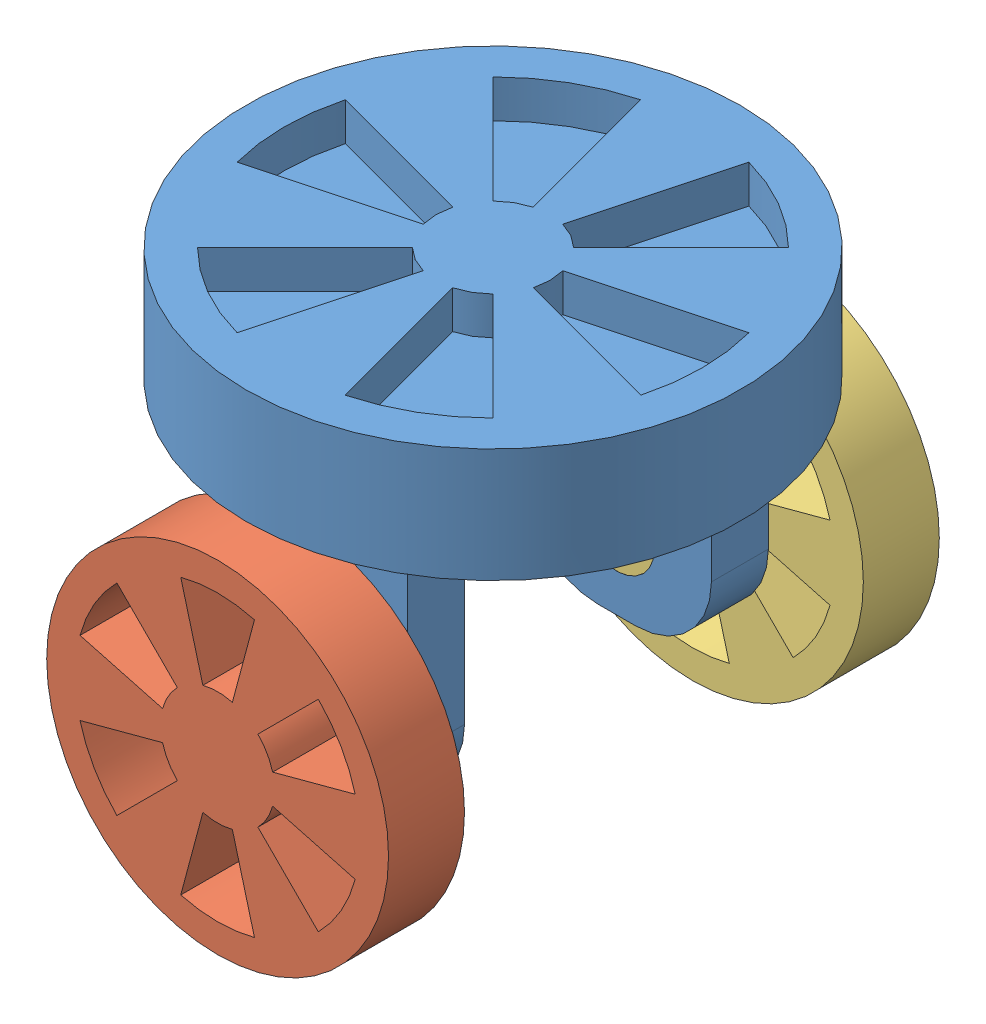
SolidWorks assembly turn_4, configuration 默认. Lengths in mm.
Overall size (130 125 145).
3 component instances, 3 part files, 4 mates.
Components (placement in the parent):
- turntable_4-1: turntable_4 [默认] at (-1.0473 18.5243 130) size (130 100 130)
- wheel_4_1-1: wheel_4_1 [默认] at (-1.0473 -31.4757 162.5) x (0 0 1) z (-1 0 0) size (40 90 90)
- wheel_4_2-1: wheel_4_2 [默认] at (-1.0473 -31.4757 97.5) x (0 0 -1) z (1 0 0) size (40 90 90)
Mates (geometry in assembly coordinates):
- 同心1: concentric: cylinder of turntable_4-1 through (-1.0473 -31.4757 65) axis (0 0 1) radius 10; cylinder of ? through (-1.0473 -31.4757 215) axis (0 0 -1) radius 10
- 重合1: coincident: plane of assembly; plane of assembly; plane of turntable_4-1 through (-26.0473 -51.4757 162.5) normal (0 0 -1); plane of wheel_4_1-1 through (-1.0473 -31.4757 162.5) normal (0 0 -1)
- 同心2: concentric: cylinder of turntable_4-1 through (-1.0473 -31.4757 65) axis (0 0 1) radius 10; cylinder of ? through (-1.0473 -31.4757 55.4262) axis (0 0 1) radius 10
- 重合2: coincident: plane of assembly; plane of assembly; plane of turntable_4-1 through (-26.0473 -51.4757 97.5) normal (0 0 1); plane of wheel_4_2-1 through (-1.0473 -31.4757 97.5) normal (0 0 1)
